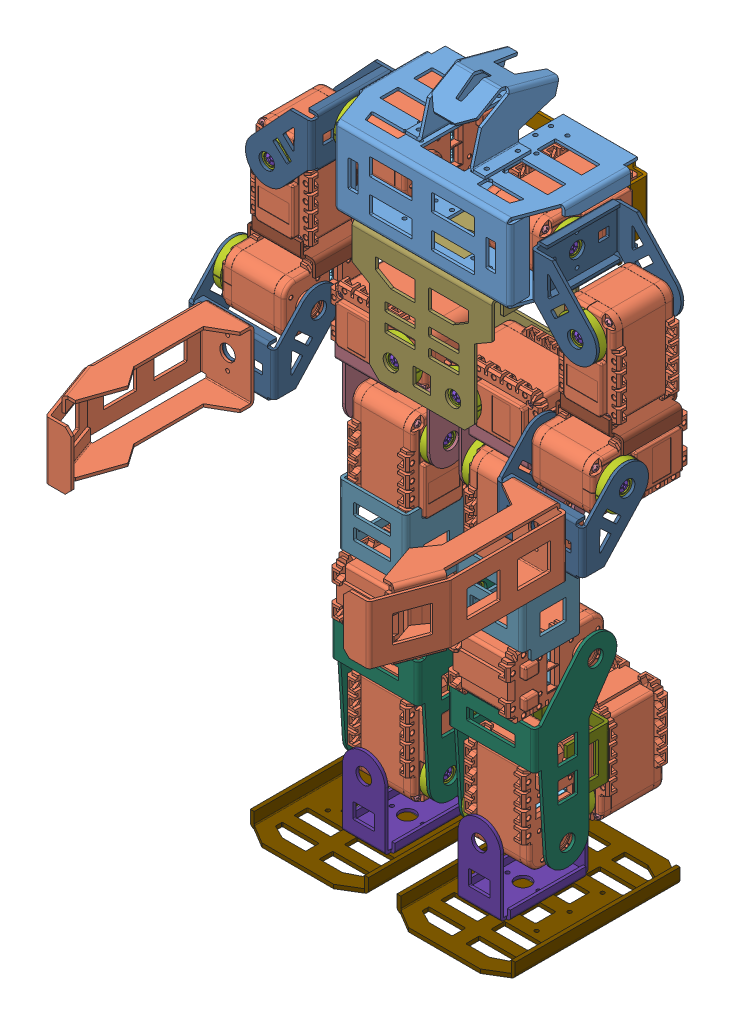
SolidWorks assembly BioloidGP1, configuration Default. Lengths in mm.
Overall size (259 349.06 195.51).
232 component instances, 20 part files, 102 mates.
Components (placement in the parent):
- FR04-E120-1: FR04-E120 [Default] at (-6.1822 -2.1819 114.2456) size (106 40.5 61.5)
- AX-12-18-A-2: AX-12-18-A [Default] at (31.961 8.8095 126.4932) x (0 1 0) z (1 0 0) size (32 50.04 40.18)
  - ASM0002_ASM-1: ASM0002_ASM [Default] at (-10.9914 -11.7476 -2.6432) size (32 50.04 40.18)
    - PRT0001-1: PRT0001 [Default] at origin size (32 50.04 38.06)
    - PRT0002-1: PRT0002 [Default] at (0 0 -2) x (-1 0 0) z (0 0 1) size (6.5 6.5 5.5)
    - PRT0003-1: PRT0003 [Default] at (9.5 8.5 14.5) x (-1 0 0) z (0 1 0) size (3.6 31.47 4.83)
    - PRT0003-2: PRT0003 [Default] at (-9.5 8.5 14.5) x (-1 0 0) z (0 1 0) size (3.6 31.47 4.83)
    - PRT0003-3: PRT0003 [Default] at (10.5 -33 14.5) x (-1 0 0) z (0 1 0) size (3.6 31.47 4.83)
    - PRT0003-4: PRT0003 [Default] at (-10.5 -33 14.5) x (-1 0 0) z (0 1 0) size (3.6 31.47 4.83)
    - PRT0004-1: PRT0004 [Default] at (5.05 -15.19 -9.75) x (1 0 0) z (0 1 0) size (9.9 9.43 4.9)
    - PRT0004-2: PRT0004 [Default] at (-4.95 -15.19 -9.75) x (1 0 0) z (0 1 0) size (9.9 9.43 4.9)
    - PRT0005-1: PRT0005 [Default] at (0 0 -18.4) x (-1 0 0) z (0 1 0) size (4.98 7 4.98)
    - PRT0006-1: PRT0006 [Default] at (0 0 19.16) x (0 1 0) z (0 0 1) size (22 22 6.7)
    - PRT0007-1: PRT0007 [Default] at (0 0 19.48) x (-1 0 0) z (0 1 0) size (5.5 9.69 5.91)
- AX-12-18-A-4: AX-12-18-A [Default] at (-44.3255 -13.1733 126.4932) x (0 -1 0) z (-1 0 0) size (32 50.04 40.18)
  - ASM0002_ASM-1: ASM0002_ASM [Default] at (-10.9914 -11.7476 -2.6432) size (32 50.04 40.18)
    - PRT0001-1: PRT0001 [Default] at origin size (32 50.04 38.06)
    - PRT0002-1: PRT0002 [Default] at (0 0 -2) x (-1 0 0) z (0 0 1) size (6.5 6.5 5.5)
    - PRT0003-1: PRT0003 [Default] at (9.5 8.5 14.5) x (-1 0 0) z (0 1 0) size (3.6 31.47 4.83)
    - PRT0003-2: PRT0003 [Default] at (-9.5 8.5 14.5) x (-1 0 0) z (0 1 0) size (3.6 31.47 4.83)
    - PRT0003-3: PRT0003 [Default] at (10.5 -33 14.5) x (-1 0 0) z (0 1 0) size (3.6 31.47 4.83)
    - PRT0003-4: PRT0003 [Default] at (-10.5 -33 14.5) x (-1 0 0) z (0 1 0) size (3.6 31.47 4.83)
    - PRT0004-1: PRT0004 [Default] at (5.05 -15.19 -9.75) x (1 0 0) z (0 1 0) size (9.9 9.43 4.9)
    - PRT0004-2: PRT0004 [Default] at (-4.95 -15.19 -9.75) x (1 0 0) z (0 1 0) size (9.9 9.43 4.9)
    - PRT0005-1: PRT0005 [Default] at (0 0 -18.4) x (-1 0 0) z (0 1 0) size (4.98 7 4.98)
    - PRT0006-1: PRT0006 [Default] at (0 0 19.16) x (0 1 0) z (0 0 1) size (22 22 6.7)
    - PRT0007-1: PRT0007 [Default] at (0 0 19.48) x (-1 0 0) z (0 1 0) size (5.5 9.69 5.91)
- FR04-E150-1: FR04-E150 [Default] at (-6.1822 -2.1819 115.0456) size (106 53 9.7)
- FR04-H102-1: FR04-H102 [Default] at (73.3178 -20.1819 114.7456) x (0 0 1) z (0 -1 0) size (45.02 34.01 42)
- FR04-H102-2: FR04-H102 [Default] at (-85.6822 -20.1819 114.7456) x (0 0 -1) z (0 -1 0) size (45.02 34.01 42)
- AX-12-18-A-7: AX-12-18-A [Default] at (84.3092 -8.4342 117.3888) size (32 50.04 40.18)
  - ASM0002_ASM-1: ASM0002_ASM [Default] at (-10.9914 -11.7476 -2.6432) size (32 50.04 40.18)
    - PRT0001-1: PRT0001 [Default] at origin size (32 50.04 38.06)
    - PRT0002-1: PRT0002 [Default] at (0 0 -2) x (-1 0 0) z (0 0 1) size (6.5 6.5 5.5)
    - PRT0003-1: PRT0003 [Default] at (9.5 8.5 14.5) x (-1 0 0) z (0 1 0) size (3.6 31.47 4.83)
    - PRT0003-2: PRT0003 [Default] at (-9.5 8.5 14.5) x (-1 0 0) z (0 1 0) size (3.6 31.47 4.83)
    - PRT0003-3: PRT0003 [Default] at (10.5 -33 14.5) x (-1 0 0) z (0 1 0) size (3.6 31.47 4.83)
    - PRT0003-4: PRT0003 [Default] at (-10.5 -33 14.5) x (-1 0 0) z (0 1 0) size (3.6 31.47 4.83)
    - PRT0004-1: PRT0004 [Default] at (5.05 -15.19 -9.75) x (1 0 0) z (0 1 0) size (9.9 9.43 4.9)
    - PRT0004-2: PRT0004 [Default] at (-4.95 -15.19 -9.75) x (1 0 0) z (0 1 0) size (9.9 9.43 4.9)
    - PRT0005-1: PRT0005 [Default] at (0 0 -18.4) x (-1 0 0) z (0 1 0) size (4.98 7 4.98)
    - PRT0006-1: PRT0006 [Default] at (0 0 19.16) x (0 1 0) z (0 0 1) size (22 22 6.7)
    - PRT0007-1: PRT0007 [Default] at (0 0 19.48) x (-1 0 0) z (0 1 0) size (5.5 9.69 5.91)
- AX-12-18-A-8: AX-12-18-A [Default] at (-74.6908 -8.4342 117.3888) size (32 50.04 40.18)
  - ASM0002_ASM-1: ASM0002_ASM [Default] at (-10.9914 -11.7476 -2.6432) size (32 50.04 40.18)
    - PRT0001-1: PRT0001 [Default] at origin size (32 50.04 38.06)
    - PRT0002-1: PRT0002 [Default] at (0 0 -2) x (-1 0 0) z (0 0 1) size (6.5 6.5 5.5)
    - PRT0003-1: PRT0003 [Default] at (9.5 8.5 14.5) x (-1 0 0) z (0 1 0) size (3.6 31.47 4.83)
    - PRT0003-2: PRT0003 [Default] at (-9.5 8.5 14.5) x (-1 0 0) z (0 1 0) size (3.6 31.47 4.83)
    - PRT0003-3: PRT0003 [Default] at (10.5 -33 14.5) x (-1 0 0) z (0 1 0) size (3.6 31.47 4.83)
    - PRT0003-4: PRT0003 [Default] at (-10.5 -33 14.5) x (-1 0 0) z (0 1 0) size (3.6 31.47 4.83)
    - PRT0004-1: PRT0004 [Default] at (5.05 -15.19 -9.75) x (1 0 0) z (0 1 0) size (9.9 9.43 4.9)
    - PRT0004-2: PRT0004 [Default] at (-4.95 -15.19 -9.75) x (1 0 0) z (0 1 0) size (9.9 9.43 4.9)
    - PRT0005-1: PRT0005 [Default] at (0 0 -18.4) x (-1 0 0) z (0 1 0) size (4.98 7 4.98)
    - PRT0006-1: PRT0006 [Default] at (0 0 19.16) x (0 1 0) z (0 0 1) size (22 22 6.7)
    - PRT0007-1: PRT0007 [Default] at (0 0 19.48) x (-1 0 0) z (0 1 0) size (5.5 9.69 5.91)
- AX-12-18-A-9: AX-12-18-A [Default] at (75.961 -66.5905 144.6932) x (0 1 0) z (1 0 0) size (32 50.04 40.18)
  - ASM0002_ASM-1: ASM0002_ASM [Default] at (-10.9914 -11.7476 -2.6432) size (32 50.04 40.18)
    - PRT0001-1: PRT0001 [Default] at origin size (32 50.04 38.06)
    - PRT0002-1: PRT0002 [Default] at (0 0 -2) x (-1 0 0) z (0 0 1) size (6.5 6.5 5.5)
    - PRT0003-1: PRT0003 [Default] at (9.5 8.5 14.5) x (-1 0 0) z (0 1 0) size (3.6 31.47 4.83)
    - PRT0003-2: PRT0003 [Default] at (-9.5 8.5 14.5) x (-1 0 0) z (0 1 0) size (3.6 31.47 4.83)
    - PRT0003-3: PRT0003 [Default] at (10.5 -33 14.5) x (-1 0 0) z (0 1 0) size (3.6 31.47 4.83)
    - PRT0003-4: PRT0003 [Default] at (-10.5 -33 14.5) x (-1 0 0) z (0 1 0) size (3.6 31.47 4.83)
    - PRT0004-1: PRT0004 [Default] at (5.05 -15.19 -9.75) x (1 0 0) z (0 1 0) size (9.9 9.43 4.9)
    - PRT0004-2: PRT0004 [Default] at (-4.95 -15.19 -9.75) x (1 0 0) z (0 1 0) size (9.9 9.43 4.9)
    - PRT0005-1: PRT0005 [Default] at (0 0 -18.4) x (-1 0 0) z (0 1 0) size (4.98 7 4.98)
    - PRT0006-1: PRT0006 [Default] at (0 0 19.16) x (0 1 0) z (0 0 1) size (22 22 6.7)
    - PRT0007-1: PRT0007 [Default] at (0 0 19.48) x (-1 0 0) z (0 1 0) size (5.5 9.69 5.91)
- AX-12-18-A-10: AX-12-18-A [Default] at (-88.3255 -88.5733 144.6932) x (0 -1 0) z (-1 0 0) size (32 50.04 40.18)
  - ASM0002_ASM-1: ASM0002_ASM [Default] at (-10.9914 -11.7476 -2.6432) size (32 50.04 40.18)
    - PRT0001-1: PRT0001 [Default] at origin size (32 50.04 38.06)
    - PRT0002-1: PRT0002 [Default] at (0 0 -2) x (-1 0 0) z (0 0 1) size (6.5 6.5 5.5)
    - PRT0003-1: PRT0003 [Default] at (9.5 8.5 14.5) x (-1 0 0) z (0 1 0) size (3.6 31.47 4.83)
    - PRT0003-2: PRT0003 [Default] at (-9.5 8.5 14.5) x (-1 0 0) z (0 1 0) size (3.6 31.47 4.83)
    - PRT0003-3: PRT0003 [Default] at (10.5 -33 14.5) x (-1 0 0) z (0 1 0) size (3.6 31.47 4.83)
    - PRT0003-4: PRT0003 [Default] at (-10.5 -33 14.5) x (-1 0 0) z (0 1 0) size (3.6 31.47 4.83)
    - PRT0004-1: PRT0004 [Default] at (5.05 -15.19 -9.75) x (1 0 0) z (0 1 0) size (9.9 9.43 4.9)
    - PRT0004-2: PRT0004 [Default] at (-4.95 -15.19 -9.75) x (1 0 0) z (0 1 0) size (9.9 9.43 4.9)
    - PRT0005-1: PRT0005 [Default] at (0 0 -18.4) x (-1 0 0) z (0 1 0) size (4.98 7 4.98)
    - PRT0006-1: PRT0006 [Default] at (0 0 19.16) x (0 1 0) z (0 0 1) size (22 22 6.7)
    - PRT0007-1: PRT0007 [Default] at (0 0 19.48) x (-1 0 0) z (0 1 0) size (5.5 9.69 5.91)
- FR04-SC101-3: FR04-SC101 [Default] at (-85.6822 -59.3819 114.7456) size (35 14.9 35)
- FR04-SC101-4: FR04-SC101 [Default] at (73.3178 -59.3819 114.7456) size (35 14.9 35)
- FR04-H102-3: FR04-H102 [Default] at (-85.6822 -77.5819 132.9456) x (-1 0 0) z (0 1 0) size (45.02 34.01 42)
- FR04-H102-4: FR04-H102 [Default] at (73.3178 -77.5819 132.9456) x (-1 0 0) z (0 1 0) size (45.02 34.01 42)
- FR04-E131-1: FR04-E131 [Default] at (-6.1822 -78.6819 114.2456) size (76 64.5 45)
- AX-12-18-A-11: AX-12-18-A [Default] at (-1.9298 -67.6905 116.8888) x (0 1 0) z (0 0 1) size (32 50.04 40.18)
  - ASM0002_ASM-1: ASM0002_ASM [Default] at (-10.9914 -11.7476 -2.6432) size (32 50.04 40.18)
    - PRT0001-1: PRT0001 [Default] at origin size (32 50.04 38.06)
    - PRT0002-1: PRT0002 [Default] at (0 0 -2) x (-1 0 0) z (0 0 1) size (6.5 6.5 5.5)
    - PRT0003-1: PRT0003 [Default] at (9.5 8.5 14.5) x (-1 0 0) z (0 1 0) size (3.6 31.47 4.83)
    - PRT0003-2: PRT0003 [Default] at (-9.5 8.5 14.5) x (-1 0 0) z (0 1 0) size (3.6 31.47 4.83)
    - PRT0003-3: PRT0003 [Default] at (10.5 -33 14.5) x (-1 0 0) z (0 1 0) size (3.6 31.47 4.83)
    - PRT0003-4: PRT0003 [Default] at (-10.5 -33 14.5) x (-1 0 0) z (0 1 0) size (3.6 31.47 4.83)
    - PRT0004-1: PRT0004 [Default] at (5.05 -15.19 -9.75) x (1 0 0) z (0 1 0) size (9.9 9.43 4.9)
    - PRT0004-2: PRT0004 [Default] at (-4.95 -15.19 -9.75) x (1 0 0) z (0 1 0) size (9.9 9.43 4.9)
    - PRT0005-1: PRT0005 [Default] at (0 0 -18.4) x (-1 0 0) z (0 1 0) size (4.98 7 4.98)
    - PRT0006-1: PRT0006 [Default] at (0 0 19.16) x (0 1 0) z (0 0 1) size (22 22 6.7)
    - PRT0007-1: PRT0007 [Default] at (0 0 19.48) x (-1 0 0) z (0 1 0) size (5.5 9.69 5.91)
- AX-12-18-A-13: AX-12-18-A [Default] at (-10.4346 -89.6733 116.8888) x (0 -1 0) z (0 0 1) size (32 50.04 40.18)
  - ASM0002_ASM-1: ASM0002_ASM [Default] at (-10.9914 -11.7476 -2.6432) size (32 50.04 40.18)
    - PRT0001-1: PRT0001 [Default] at origin size (32 50.04 38.06)
    - PRT0002-1: PRT0002 [Default] at (0 0 -2) x (-1 0 0) z (0 0 1) size (6.5 6.5 5.5)
    - PRT0003-1: PRT0003 [Default] at (9.5 8.5 14.5) x (-1 0 0) z (0 1 0) size (3.6 31.47 4.83)
    - PRT0003-2: PRT0003 [Default] at (-9.5 8.5 14.5) x (-1 0 0) z (0 1 0) size (3.6 31.47 4.83)
    - PRT0003-3: PRT0003 [Default] at (10.5 -33 14.5) x (-1 0 0) z (0 1 0) size (3.6 31.47 4.83)
    - PRT0003-4: PRT0003 [Default] at (-10.5 -33 14.5) x (-1 0 0) z (0 1 0) size (3.6 31.47 4.83)
    - PRT0004-1: PRT0004 [Default] at (5.05 -15.19 -9.75) x (1 0 0) z (0 1 0) size (9.9 9.43 4.9)
    - PRT0004-2: PRT0004 [Default] at (-4.95 -15.19 -9.75) x (1 0 0) z (0 1 0) size (9.9 9.43 4.9)
    - PRT0005-1: PRT0005 [Default] at (0 0 -18.4) x (-1 0 0) z (0 1 0) size (4.98 7 4.98)
    - PRT0006-1: PRT0006 [Default] at (0 0 19.16) x (0 1 0) z (0 0 1) size (22 22 6.7)
    - PRT0007-1: PRT0007 [Default] at (0 0 19.48) x (-1 0 0) z (0 1 0) size (5.5 9.69 5.91)
- FR04-HC110-1: FR04-HC110 [Default] at (-36.1822 -120.4819 114.2456) size (45 42.8 35)
- FR04-HC110-2: FR04-HC110 [Default] at (23.8178 -120.4819 114.2456) x (-1 0 0) z (0 0 -1) size (45 42.8 35)
- AX-12-18-A-16: AX-12-18-A [Default] at (21.1745 -108.7342 125.237) x (0 0 1) z (-1 0 0) size (32 50.04 40.18)
  - ASM0002_ASM-1: ASM0002_ASM [Default] at (-10.9914 -11.7476 -2.6432) size (32 50.04 40.18)
    - PRT0001-1: PRT0001 [Default] at origin size (32 50.04 38.06)
    - PRT0002-1: PRT0002 [Default] at (0 0 -2) x (-1 0 0) z (0 0 1) size (6.5 6.5 5.5)
    - PRT0003-1: PRT0003 [Default] at (9.5 8.5 14.5) x (-1 0 0) z (0 1 0) size (3.6 31.47 4.83)
    - PRT0003-2: PRT0003 [Default] at (-9.5 8.5 14.5) x (-1 0 0) z (0 1 0) size (3.6 31.47 4.83)
    - PRT0003-3: PRT0003 [Default] at (10.5 -33 14.5) x (-1 0 0) z (0 1 0) size (3.6 31.47 4.83)
    - PRT0003-4: PRT0003 [Default] at (-10.5 -33 14.5) x (-1 0 0) z (0 1 0) size (3.6 31.47 4.83)
    - PRT0004-1: PRT0004 [Default] at (5.05 -15.19 -9.75) x (1 0 0) z (0 1 0) size (9.9 9.43 4.9)
    - PRT0004-2: PRT0004 [Default] at (-4.95 -15.19 -9.75) x (1 0 0) z (0 1 0) size (9.9 9.43 4.9)
    - PRT0005-1: PRT0005 [Default] at (0 0 -18.4) x (-1 0 0) z (0 1 0) size (4.98 7 4.98)
    - PRT0006-1: PRT0006 [Default] at (0 0 19.16) x (0 1 0) z (0 0 1) size (22 22 6.7)
    - PRT0007-1: PRT0007 [Default] at (0 0 19.48) x (-1 0 0) z (0 1 0) size (5.5 9.69 5.91)
- AX-12-18-A-17: AX-12-18-A [Default] at (-33.539 -108.7342 103.2542) x (0 0 -1) z (1 0 0) size (32 50.04 40.18)
  - ASM0002_ASM-1: ASM0002_ASM [Default] at (-10.9914 -11.7476 -2.6432) size (32 50.04 40.18)
    - PRT0001-1: PRT0001 [Default] at origin size (32 50.04 38.06)
    - PRT0002-1: PRT0002 [Default] at (0 0 -2) x (-1 0 0) z (0 0 1) size (6.5 6.5 5.5)
    - PRT0003-1: PRT0003 [Default] at (9.5 8.5 14.5) x (-1 0 0) z (0 1 0) size (3.6 31.47 4.83)
    - PRT0003-2: PRT0003 [Default] at (-9.5 8.5 14.5) x (-1 0 0) z (0 1 0) size (3.6 31.47 4.83)
    - PRT0003-3: PRT0003 [Default] at (10.5 -33 14.5) x (-1 0 0) z (0 1 0) size (3.6 31.47 4.83)
    - PRT0003-4: PRT0003 [Default] at (-10.5 -33 14.5) x (-1 0 0) z (0 1 0) size (3.6 31.47 4.83)
    - PRT0004-1: PRT0004 [Default] at (5.05 -15.19 -9.75) x (1 0 0) z (0 1 0) size (9.9 9.43 4.9)
    - PRT0004-2: PRT0004 [Default] at (-4.95 -15.19 -9.75) x (1 0 0) z (0 1 0) size (9.9 9.43 4.9)
    - PRT0005-1: PRT0005 [Default] at (0 0 -18.4) x (-1 0 0) z (0 1 0) size (4.98 7 4.98)
    - PRT0006-1: PRT0006 [Default] at (0 0 19.16) x (0 1 0) z (0 0 1) size (22 22 6.7)
    - PRT0007-1: PRT0007 [Default] at (0 0 19.48) x (-1 0 0) z (0 1 0) size (5.5 9.69 5.91)
- FR04-SC110-1: FR04-SC110 [Default] at (-36.1822 -120.1819 113.9456) size (35 37.2 29.5)
- FR04-SC110-2: FR04-SC110 [Default] at (23.8178 -120.1819 113.9456) size (35 37.2 29.5)
- AX-12-18-A-18: AX-12-18-A [Default] at (21.1745 -183.8905 87.9979) x (0 1 0) z (-1 0 0) size (32 50.04 40.18)
  - ASM0002_ASM-1: ASM0002_ASM [Default] at (-10.9914 -11.7476 -2.6432) size (32 50.04 40.18)
    - PRT0001-1: PRT0001 [Default] at origin size (32 50.04 38.06)
    - PRT0002-1: PRT0002 [Default] at (0 0 -2) x (-1 0 0) z (0 0 1) size (6.5 6.5 5.5)
    - PRT0003-1: PRT0003 [Default] at (9.5 8.5 14.5) x (-1 0 0) z (0 1 0) size (3.6 31.47 4.83)
    - PRT0003-2: PRT0003 [Default] at (-9.5 8.5 14.5) x (-1 0 0) z (0 1 0) size (3.6 31.47 4.83)
    - PRT0003-3: PRT0003 [Default] at (10.5 -33 14.5) x (-1 0 0) z (0 1 0) size (3.6 31.47 4.83)
    - PRT0003-4: PRT0003 [Default] at (-10.5 -33 14.5) x (-1 0 0) z (0 1 0) size (3.6 31.47 4.83)
    - PRT0004-1: PRT0004 [Default] at (5.05 -15.19 -9.75) x (1 0 0) z (0 1 0) size (9.9 9.43 4.9)
    - PRT0004-2: PRT0004 [Default] at (-4.95 -15.19 -9.75) x (1 0 0) z (0 1 0) size (9.9 9.43 4.9)
    - PRT0005-1: PRT0005 [Default] at (0 0 -18.4) x (-1 0 0) z (0 1 0) size (4.98 7 4.98)
    - PRT0006-1: PRT0006 [Default] at (0 0 19.16) x (0 1 0) z (0 0 1) size (22 22 6.7)
    - PRT0007-1: PRT0007 [Default] at (0 0 19.48) x (-1 0 0) z (0 1 0) size (5.5 9.69 5.91)
- AX-12-18-A-19: AX-12-18-A [Default] at (-33.539 -205.8733 87.9979) x (0 -1 0) z (1 0 0) size (32 50.04 40.18)
  - ASM0002_ASM-1: ASM0002_ASM [Default] at (-10.9914 -11.7476 -2.6432) size (32 50.04 40.18)
    - PRT0001-1: PRT0001 [Default] at origin size (32 50.04 38.06)
    - PRT0002-1: PRT0002 [Default] at (0 0 -2) x (-1 0 0) z (0 0 1) size (6.5 6.5 5.5)
    - PRT0003-1: PRT0003 [Default] at (9.5 8.5 14.5) x (-1 0 0) z (0 1 0) size (3.6 31.47 4.83)
    - PRT0003-2: PRT0003 [Default] at (-9.5 8.5 14.5) x (-1 0 0) z (0 1 0) size (3.6 31.47 4.83)
    - PRT0003-3: PRT0003 [Default] at (10.5 -33 14.5) x (-1 0 0) z (0 1 0) size (3.6 31.47 4.83)
    - PRT0003-4: PRT0003 [Default] at (-10.5 -33 14.5) x (-1 0 0) z (0 1 0) size (3.6 31.47 4.83)
    - PRT0004-1: PRT0004 [Default] at (5.05 -15.19 -9.75) x (1 0 0) z (0 1 0) size (9.9 9.43 4.9)
    - PRT0004-2: PRT0004 [Default] at (-4.95 -15.19 -9.75) x (1 0 0) z (0 1 0) size (9.9 9.43 4.9)
    - PRT0005-1: PRT0005 [Default] at (0 0 -18.4) x (-1 0 0) z (0 1 0) size (4.98 7 4.98)
    - PRT0006-1: PRT0006 [Default] at (0 0 19.16) x (0 1 0) z (0 0 1) size (22 22 6.7)
    - PRT0007-1: PRT0007 [Default] at (0 0 19.48) x (-1 0 0) z (0 1 0) size (5.5 9.69 5.91)
- FR04-H120-1: FR04-H120 [Default] at (-36.1822 -269.8819 114.2456) x (-1 0 0) z (0 0 1) size (45 97 42.5)
- FR04-H120-2: FR04-H120 [Default] at (23.8178 -269.8819 114.2456) x (-1 0 0) z (0 0 1) size (45 97 42.5)
- AX-12-18-A-20: AX-12-18-A [Default] at (-33.539 -281.6295 125.237) x (0 0 1) z (1 0 0) size (32 50.04 40.18)
  - ASM0002_ASM-1: ASM0002_ASM [Default] at (-10.9914 -11.7476 -2.6432) size (32 50.04 40.18)
    - PRT0001-1: PRT0001 [Default] at origin size (32 50.04 38.06)
    - PRT0002-1: PRT0002 [Default] at (0 0 -2) x (-1 0 0) z (0 0 1) size (6.5 6.5 5.5)
    - PRT0003-1: PRT0003 [Default] at (9.5 8.5 14.5) x (-1 0 0) z (0 1 0) size (3.6 31.47 4.83)
    - PRT0003-2: PRT0003 [Default] at (-9.5 8.5 14.5) x (-1 0 0) z (0 1 0) size (3.6 31.47 4.83)
    - PRT0003-3: PRT0003 [Default] at (10.5 -33 14.5) x (-1 0 0) z (0 1 0) size (3.6 31.47 4.83)
    - PRT0003-4: PRT0003 [Default] at (-10.5 -33 14.5) x (-1 0 0) z (0 1 0) size (3.6 31.47 4.83)
    - PRT0004-1: PRT0004 [Default] at (5.05 -15.19 -9.75) x (1 0 0) z (0 1 0) size (9.9 9.43 4.9)
    - PRT0004-2: PRT0004 [Default] at (-4.95 -15.19 -9.75) x (1 0 0) z (0 1 0) size (9.9 9.43 4.9)
    - PRT0005-1: PRT0005 [Default] at (0 0 -18.4) x (-1 0 0) z (0 1 0) size (4.98 7 4.98)
    - PRT0006-1: PRT0006 [Default] at (0 0 19.16) x (0 1 0) z (0 0 1) size (22 22 6.7)
    - PRT0007-1: PRT0007 [Default] at (0 0 19.48) x (-1 0 0) z (0 1 0) size (5.5 9.69 5.91)
- AX-12-18-A-21: AX-12-18-A [Default] at (21.1745 -281.6295 103.2542) x (0 0 -1) z (-1 0 0) size (32 50.04 40.18)
  - ASM0002_ASM-1: ASM0002_ASM [Default] at (-10.9914 -11.7476 -2.6432) size (32 50.04 40.18)
    - PRT0001-1: PRT0001 [Default] at origin size (32 50.04 38.06)
    - PRT0002-1: PRT0002 [Default] at (0 0 -2) x (-1 0 0) z (0 0 1) size (6.5 6.5 5.5)
    - PRT0003-1: PRT0003 [Default] at (9.5 8.5 14.5) x (-1 0 0) z (0 1 0) size (3.6 31.47 4.83)
    - PRT0003-2: PRT0003 [Default] at (-9.5 8.5 14.5) x (-1 0 0) z (0 1 0) size (3.6 31.47 4.83)
    - PRT0003-3: PRT0003 [Default] at (10.5 -33 14.5) x (-1 0 0) z (0 1 0) size (3.6 31.47 4.83)
    - PRT0003-4: PRT0003 [Default] at (-10.5 -33 14.5) x (-1 0 0) z (0 1 0) size (3.6 31.47 4.83)
    - PRT0004-1: PRT0004 [Default] at (5.05 -15.19 -9.75) x (1 0 0) z (0 1 0) size (9.9 9.43 4.9)
    - PRT0004-2: PRT0004 [Default] at (-4.95 -15.19 -9.75) x (1 0 0) z (0 1 0) size (9.9 9.43 4.9)
    - PRT0005-1: PRT0005 [Default] at (0 0 -18.4) x (-1 0 0) z (0 1 0) size (4.98 7 4.98)
    - PRT0006-1: PRT0006 [Default] at (0 0 19.16) x (0 1 0) z (0 0 1) size (22 22 6.7)
    - PRT0007-1: PRT0007 [Default] at (0 0 19.48) x (-1 0 0) z (0 1 0) size (5.5 9.69 5.91)
- FR04-X101-1: FR04-X101 [Default] at (-36.1822 -247.6819 100.9456) x (1 0 0) z (0 1 0) size (35 22.5 26.5)
- FR04-X101-2: FR04-X101 [Default] at (23.8178 -247.6819 100.9456) x (1 0 0) z (0 1 0) size (35 22.5 26.5)
- AX-12-18-A-22: AX-12-18-A [Default] at (-46.9736 -281.7295 73.5888) x (-1 0 0) z (0 0 1) size (32 50.04 40.18)
  - ASM0002_ASM-1: ASM0002_ASM [Default] at (-10.9914 -11.7476 -2.6432) size (32 50.04 40.18)
    - PRT0001-1: PRT0001 [Default] at origin size (32 50.04 38.06)
    - PRT0002-1: PRT0002 [Default] at (0 0 -2) x (-1 0 0) z (0 0 1) size (6.5 6.5 5.5)
    - PRT0003-1: PRT0003 [Default] at (9.5 8.5 14.5) x (-1 0 0) z (0 1 0) size (3.6 31.47 4.83)
    - PRT0003-2: PRT0003 [Default] at (-9.5 8.5 14.5) x (-1 0 0) z (0 1 0) size (3.6 31.47 4.83)
    - PRT0003-3: PRT0003 [Default] at (10.5 -33 14.5) x (-1 0 0) z (0 1 0) size (3.6 31.47 4.83)
    - PRT0003-4: PRT0003 [Default] at (-10.5 -33 14.5) x (-1 0 0) z (0 1 0) size (3.6 31.47 4.83)
    - PRT0004-1: PRT0004 [Default] at (5.05 -15.19 -9.75) x (1 0 0) z (0 1 0) size (9.9 9.43 4.9)
    - PRT0004-2: PRT0004 [Default] at (-4.95 -15.19 -9.75) x (1 0 0) z (0 1 0) size (9.9 9.43 4.9)
    - PRT0005-1: PRT0005 [Default] at (0 0 -18.4) x (-1 0 0) z (0 1 0) size (4.98 7 4.98)
    - PRT0006-1: PRT0006 [Default] at (0 0 19.16) x (0 1 0) z (0 0 1) size (22 22 6.7)
    - PRT0007-1: PRT0007 [Default] at (0 0 19.48) x (-1 0 0) z (0 1 0) size (5.5 9.69 5.91)
- AX-12-18-A-23: AX-12-18-A [Default] at (12.6264 -281.7295 73.5888) x (-1 0 0) z (0 0 1) size (32 50.04 40.18)
  - ASM0002_ASM-1: ASM0002_ASM [Default] at (-10.9914 -11.7476 -2.6432) size (32 50.04 40.18)
    - PRT0001-1: PRT0001 [Default] at origin size (32 50.04 38.06)
    - PRT0002-1: PRT0002 [Default] at (0 0 -2) x (-1 0 0) z (0 0 1) size (6.5 6.5 5.5)
    - PRT0003-1: PRT0003 [Default] at (9.5 8.5 14.5) x (-1 0 0) z (0 1 0) size (3.6 31.47 4.83)
    - PRT0003-2: PRT0003 [Default] at (-9.5 8.5 14.5) x (-1 0 0) z (0 1 0) size (3.6 31.47 4.83)
    - PRT0003-3: PRT0003 [Default] at (10.5 -33 14.5) x (-1 0 0) z (0 1 0) size (3.6 31.47 4.83)
    - PRT0003-4: PRT0003 [Default] at (-10.5 -33 14.5) x (-1 0 0) z (0 1 0) size (3.6 31.47 4.83)
    - PRT0004-1: PRT0004 [Default] at (5.05 -15.19 -9.75) x (1 0 0) z (0 1 0) size (9.9 9.43 4.9)
    - PRT0004-2: PRT0004 [Default] at (-4.95 -15.19 -9.75) x (1 0 0) z (0 1 0) size (9.9 9.43 4.9)
    - PRT0005-1: PRT0005 [Default] at (0 0 -18.4) x (-1 0 0) z (0 1 0) size (4.98 7 4.98)
    - PRT0006-1: PRT0006 [Default] at (0 0 19.16) x (0 1 0) z (0 0 1) size (22 22 6.7)
    - PRT0007-1: PRT0007 [Default] at (0 0 19.48) x (-1 0 0) z (0 1 0) size (5.5 9.69 5.91)
- FR04-H101-1: FR04-H101 [Default] at (-35.9822 -269.9819 114.4456) x (0 0 1) z (1 0 0) size (45 41 26)
- FR04-H101-2: FR04-H101 [Default] at (23.6178 -269.9819 114.4456) x (0 0 -1) z (-1 0 0) size (45 41 26)
- FR04-E160-1: FR04-E160 [Default] at (-43.9822 -299.9819 114.4456) size (61 8 97)
- FR04-E160-2: FR04-E160 [Default] at (31.6178 -299.9819 114.4456) size (61 8 97)
- FR04-E175-1: FR04-E175 [Default] at (-6.1822 15.3181 124.7294) x (1 0 0) z (0 0.258819 0.965926) size (41 31.63 43.12)
- FR04-E180-1: FR04-E180 [Default] at (-85.6822 -95.5819 155.9456) x (1 0 0) z (0 1 0) size (27 91.51 36)
- FR04-E180-2: FR04-E180 [Default] at (73.3178 -95.5819 155.9456) x (-1 0 0) z (0 -1 0) size (27 91.51 36)
Mates (geometry in assembly coordinates):
- Coincident2: coincident anti-aligned: plane of FR04-E120-1 through (45.3178 -2.1819 114.2456) normal (-1 0 0); plane of AX-12-18-A-2/ASM0002_ASM-1/PRT0001-1 through (45.3178 -2.1819 114.7456) normal (1 0 0)
- Coincident4: coincident anti-aligned: plane of FR04-E120-1 through (-59.2222 13.8181 135.9356) normal (0 -1 0); plane of AX-12-18-A-2/ASM0002_ASM-1/PRT0001-1 through (45.3178 13.8181 112.7456) normal (0 1 0)
- Coincident6: coincident anti-aligned: plane of FR04-E120-1 through (-57.6822 -2.1819 114.2456) normal (1 0 0); plane of AX-12-18-A-4/ASM0002_ASM-1/PRT0001-1 through (-57.6822 -2.1819 114.7456) normal (-1 0 0)
- Coincident7: coincident anti-aligned: plane of FR04-E120-1 through (-59.2222 13.8181 135.9356) normal (0 -1 0); plane of AX-12-18-A-4/ASM0002_ASM-1/PRT0001-1 through (-57.6822 13.8181 79.7456) normal (0 1 0)
- Coincident8: coincident anti-aligned: plane of FR04-E120-1 through (-59.2222 13.8181 135.9356) normal (0 -1 0); plane of FR04-E150-1 through (-6.1822 13.8181 115.0456) normal (0 1 0)
- Coincident9: coincident anti-aligned: plane of FR04-E120-1 through (-59.2222 -23.6819 74.0556) normal (0 1 0); plane of ? through (-6.1822 -23.6819 114.2456) normal (0 -1 0)
- Coincident10: coincident anti-aligned: plane of FR04-E120-1 through (-6.1822 -2.1819 82.2456) normal (0 0 -1); plane of FR04-E150-1 through (-6.1822 -2.1819 82.2456) normal (0 0 1)
- Coincident11: coincident aligned: plane of FR04-E120-1 through (46.8178 -2.1819 114.2456) normal (1 0 0); plane of FR04-E150-1 through (46.8178 8.0181 82.2456) normal (1 0 0)
- Coincident12: coincident anti-aligned: plane of AX-12-18-A-2/ASM0002_ASM-1/PRT0001-1 through (48.3178 7.8181 82.2456) normal (0 0 -1); plane of FR04-E150-1 through (-6.1822 -2.1819 82.2456) normal (0 0 1)
- Coincident13: coincident anti-aligned: plane of AX-12-18-A-4/ASM0002_ASM-1/PRT0001-1 through (-60.6822 -12.1819 82.2456) normal (0 0 -1); plane of FR04-E150-1 through (-6.1822 -2.1819 82.2456) normal (0 0 1)
- Coincident14: coincident anti-aligned: plane of AX-12-18-A-2/ASM0002_ASM-1/PRT0006-1 through (50.3178 -2.1819 114.7456) normal (1 0 0); plane of FR04-H102-1 through (50.3178 9.7781 93.4256) normal (-1 0 0)
- Concentric1: concentric aligned: cylinder of AX-12-18-A-2/ASM0002_ASM-1/PRT0006-1 through (51.1778 -2.1819 114.7456) axis (1 0 0) radius 2.9; cylinder of FR04-H102-1 through (51.8178 -2.1819 114.7456) axis (1 0 0) radius 4
- Coincident15: coincident anti-aligned: plane of AX-12-18-A-4/ASM0002_ASM-1/PRT0006-1 through (-62.6822 -2.1819 114.7456) normal (-1 0 0); plane of FR04-H102-2 through (-62.6822 9.7781 136.0656) normal (1 0 0)
- Concentric2: concentric aligned: cylinder of AX-12-18-A-4/ASM0002_ASM-1/PRT0006-1 through (-63.5422 -2.1819 114.7456) axis (-1 0 0) radius 2.9; cylinder of FR04-H102-2 through (-64.1822 -2.1819 114.7456) axis (-1 0 0) radius 4
- Coincident16: coincident anti-aligned: plane of FR04-H102-1 through (51.6778 9.6181 135.7456) normal (0 0 -1); plane of AX-12-18-A-7/ASM0002_ASM-1/PRT0006-1 through (73.3178 -20.1819 135.7456) normal (0 0 1)
- Concentric3: concentric anti-aligned: cylinder of FR04-H102-1 through (73.3178 -20.1819 135.7456) axis (0 0 -1) radius 4; cylinder of AX-12-18-A-7/ASM0002_ASM-1/PRT0006-1 through (73.3178 -20.1819 136.6056) axis (0 0 1) radius 2.9
- Coincident18: coincident anti-aligned: plane of FR04-H102-2 through (-97.3232 9.6181 135.7456) normal (0 0 -1); plane of AX-12-18-A-8/ASM0002_ASM-1/PRT0006-1 through (-85.6822 -20.1819 135.7456) normal (0 0 1)
- Concentric4: concentric anti-aligned: cylinder of FR04-H102-2 through (-85.6822 -20.1819 135.7456) axis (0 0 -1) radius 4; cylinder of AX-12-18-A-8/ASM0002_ASM-1/PRT0006-1 through (-85.6822 -20.1819 136.6056) axis (0 0 1) radius 2.9
- Coincident19: coincident anti-aligned: plane of AX-12-18-A-7/ASM0002_ASM-1/PRT0001-1 through (73.3178 -20.1819 130.7456) normal (0 0 1); plane of FR04-SC101-4 through (60.8178 -52.6819 130.7456) normal (0 0 -1)
- Coincident20: coincident anti-aligned: plane of AX-12-18-A-8/ASM0002_ASM-1/PRT0001-1 through (-85.6822 -20.1819 130.7456) normal (0 0 1); plane of FR04-SC101-3 through (-98.1822 -52.6819 130.7456) normal (0 0 -1)
- Coincident21: coincident anti-aligned: plane of AX-12-18-A-7/ASM0002_ASM-1/PRT0001-1 through (83.3178 -52.6819 133.7456) normal (0 -1 0); plane of FR04-SC101-4 through (73.3178 -52.6819 114.7456) normal (0 1 0)
- Coincident22: coincident anti-aligned: plane of AX-12-18-A-8/ASM0002_ASM-1/PRT0001-1 through (-75.6822 -52.6819 133.7456) normal (0 -1 0); plane of FR04-SC101-3 through (-85.6822 -52.6819 114.7456) normal (0 1 0)
- Coincident23: coincident aligned: plane of AX-12-18-A-7/ASM0002_ASM-1/PRT0001-1 through (60.8178 -58.6819 130.7456) normal (-1 0 0); plane of FR04-SC101-4 through (60.8178 -60.8819 97.2456) normal (-1 0 0)
- Coincident24: coincident aligned: plane of AX-12-18-A-8/ASM0002_ASM-1/PRT0001-1 through (-73.1822 -55.6819 130.7456) normal (1 0 0); plane of FR04-SC101-3 through (-73.1822 -60.8819 132.2456) normal (1 0 0)
- Coincident25: coincident anti-aligned: plane of AX-12-18-A-9/ASM0002_ASM-1/PRT0001-1 through (89.3178 -77.5819 132.9456) normal (1 0 0); plane of FR04-SC101-4 through (89.3178 -67.5819 99.7456) normal (-1 0 0)
- Coincident26: coincident anti-aligned: plane of AX-12-18-A-9/ASM0002_ASM-1/PRT0001-1 through (92.3178 -67.5819 144.4456) normal (0 1 0); plane of FR04-SC101-4 through (73.3178 -67.5819 114.7456) normal (0 -1 0)
- Coincident28: coincident aligned: plane of AX-12-18-A-9/ASM0002_ASM-1/PRT0001-1 through (89.3178 -93.5819 129.7456) normal (0 0 1); plane of FR04-SC101-4 through (90.8178 -60.8819 129.7456) normal (0 0 1)
- Coincident29: coincident anti-aligned: plane of AX-12-18-A-10/ASM0002_ASM-1/PRT0001-1 through (-101.6822 -77.5819 132.9456) normal (-1 0 0); plane of FR04-SC101-3 through (-101.6822 -67.5819 129.7456) normal (1 0 0)
- Coincident30: coincident anti-aligned: plane of AX-12-18-A-10/ASM0002_ASM-1/PRT0001-1 through (-104.6822 -67.5819 100.4456) normal (0 1 0); plane of FR04-SC101-3 through (-85.6822 -67.5819 114.7456) normal (0 -1 0)
- Coincident31: coincident aligned: plane of AX-12-18-A-10/ASM0002_ASM-1/PRT0001-1 through (-101.6822 -61.5819 129.7456) normal (0 0 1); plane of FR04-SC101-3 through (-103.1822 -59.3819 129.7456) normal (0 0 1)
- Coincident32: coincident anti-aligned: plane of AX-12-18-A-9/ASM0002_ASM-1/PRT0006-1 through (94.3178 -77.5819 132.9456) normal (1 0 0); plane of FR04-H102-4 through (94.3178 -107.3819 121.3046) normal (-1 0 0)
- Concentric5: concentric anti-aligned: cylinder of AX-12-18-A-9/ASM0002_ASM-1/PRT0006-1 through (95.1778 -77.5819 132.9456) axis (1 0 0) radius 2.9; cylinder of FR04-H102-4 through (94.3178 -77.5819 132.9456) axis (-1 0 0) radius 4
- Coincident33: coincident anti-aligned: plane of AX-12-18-A-10/ASM0002_ASM-1/PRT0006-1 through (-106.6822 -77.5819 132.9456) normal (-1 0 0); plane of FR04-H102-3 through (-106.6822 -107.3819 154.5856) normal (1 0 0)
- Concentric6: concentric anti-aligned: cylinder of AX-12-18-A-10/ASM0002_ASM-1/PRT0006-1 through (-107.5422 -77.5819 132.9456) axis (-1 0 0) radius 2.9; cylinder of FR04-H102-3 through (-106.6822 -77.5819 132.9456) axis (1 0 0) radius 4
- Coincident37: coincident anti-aligned: plane of FR04-E131-1 through (29.8178 -89.6819 135.2456) normal (0 0 -1); plane of AX-12-18-A-11/ASM0002_ASM-1/PRT0006-1 through (9.8178 -78.6819 135.2456) normal (0 0 1)
- Coincident38: coincident anti-aligned: plane of FR04-E131-1 through (29.8178 -89.6819 135.2456) normal (0 0 -1); plane of AX-12-18-A-13/ASM0002_ASM-1/PRT0006-1 through (-22.1822 -78.6819 135.2456) normal (0 0 1)
- Concentric10: concentric anti-aligned: cylinder of FR04-E131-1 through (9.8178 -78.6819 135.2456) axis (0 0 -1) radius 4; cylinder of AX-12-18-A-11/ASM0002_ASM-1/PRT0006-1 through (9.8178 -78.6819 136.1056) axis (0 0 1) radius 2.9
- Concentric11: concentric anti-aligned: cylinder of FR04-E131-1 through (-22.1822 -78.6819 135.2456) axis (0 0 -1) radius 4; cylinder of AX-12-18-A-13/ASM0002_ASM-1/PRT0006-1 through (-22.1822 -78.6819 136.1056) axis (0 0 1) radius 2.9
- Coincident39: coincident anti-aligned: plane of AX-12-18-A-13/ASM0002_ASM-1/PRT0001-1 through (-22.1822 -78.6819 130.2456) normal (0 0 1); plane of FR04-HC110-1 through (-55.9822 -88.6819 130.2456) normal (0 0 -1)
- Coincident40: coincident anti-aligned: plane of AX-12-18-A-11/ASM0002_ASM-1/PRT0001-1 through (9.8178 -78.6819 130.2456) normal (0 0 1); plane of FR04-HC110-2 through (13.0178 -88.6819 130.2456) normal (0 0 -1)
- Coincident41: coincident aligned: plane of AX-12-18-A-11/ASM0002_ASM-1/PRT0001-1 through (43.6178 -93.1819 130.2456) normal (1 0 0); plane of FR04-HC110-2 through (43.6178 -94.9819 131.7456) normal (1 0 0)
- Coincident42: coincident aligned: plane of AX-12-18-A-13/ASM0002_ASM-1/PRT0001-1 through (-55.9822 -93.1819 130.2456) normal (-1 0 0); plane of FR04-HC110-1 through (-55.9822 -96.4819 131.7456) normal (-1 0 0)
- Coincident43: coincident anti-aligned: plane of AX-12-18-A-13/ASM0002_ASM-1/PRT0001-1 through (-10.6822 -88.6819 133.2456) normal (0 -1 0); plane of FR04-HC110-1 through (-36.1822 -88.6819 114.2456) normal (0 1 0)
- Coincident44: coincident anti-aligned: plane of AX-12-18-A-11/ASM0002_ASM-1/PRT0001-1 through (42.3178 -88.6819 133.2456) normal (0 -1 0); plane of FR04-HC110-2 through (23.8178 -88.6819 114.2456) normal (0 1 0)
- Coincident45: coincident anti-aligned: plane of FR04-HC110-1 through (-15.1822 -138.3645 103.2456) normal (-1 0 0); plane of AX-12-18-A-17/ASM0002_ASM-1/PRT0006-1 through (-15.1822 -120.4819 114.2456) normal (1 0 0)
- Concentric12: concentric anti-aligned: cylinder of FR04-HC110-1 through (-15.1822 -120.4819 114.2456) axis (-1 0 0) radius 4; cylinder of AX-12-18-A-17/ASM0002_ASM-1/PRT0006-1 through (-14.3222 -120.4819 114.2456) axis (1 0 0) radius 2.9
- Coincident46: coincident anti-aligned: plane of FR04-HC110-2 through (2.8178 -138.3645 125.2456) normal (1 0 0); plane of AX-12-18-A-16/ASM0002_ASM-1/PRT0006-1 through (2.8178 -120.4819 114.2456) normal (-1 0 0)
- Concentric13: concentric anti-aligned: cylinder of FR04-HC110-2 through (2.8178 -120.4819 114.2456) axis (1 0 0) radius 4; cylinder of AX-12-18-A-16/ASM0002_ASM-1/PRT0006-1 through (1.9578 -120.4819 114.2456) axis (-1 0 0) radius 2.9
- Coincident47: coincident anti-aligned: plane of AX-12-18-A-17/ASM0002_ASM-1/PRT0001-1 through (-20.1822 -120.4819 114.2456) normal (1 0 0); plane of FR04-SC110-1 through (-20.1822 -120.1819 113.9456) normal (-1 0 0)
- Coincident48: coincident anti-aligned: plane of AX-12-18-A-16/ASM0002_ASM-1/PRT0001-1 through (7.8178 -120.4819 114.2456) normal (-1 0 0); plane of FR04-SC110-2 through (7.8178 -178.8819 102.9456) normal (1 0 0)
- Coincident49: coincident anti-aligned: plane of AX-12-18-A-16/ASM0002_ASM-1/PRT0001-1 through (4.8178 -108.9819 124.2456) normal (0 0 1); plane of FR04-SC110-2 through (41.3178 -152.9819 124.2456) normal (0 0 -1)
- Coincident50: coincident anti-aligned: plane of AX-12-18-A-16/ASM0002_ASM-1/PRT0001-1 through (4.8178 -152.9819 124.2456) normal (0 -1 0); plane of FR04-SC110-2 through (41.3178 -152.9819 102.9456) normal (0 1 0)
- Coincident51: coincident anti-aligned: plane of AX-12-18-A-17/ASM0002_ASM-1/PRT0001-1 through (-17.1822 -152.9819 104.2456) normal (0 -1 0); plane of FR04-SC110-1 through (-53.6832 -152.9819 124.2456) normal (0 1 0)
- Coincident52: coincident anti-aligned: plane of AX-12-18-A-17/ASM0002_ASM-1/PRT0001-1 through (-17.1822 -152.9819 124.2456) normal (0 0 1); plane of FR04-SC110-1 through (-53.6832 -147.6819 124.2456) normal (0 0 -1)
- Coincident53: coincident anti-aligned: plane of FR04-SC110-1 through (-18.6822 -184.8819 102.9456) normal (0 -1 0); plane of AX-12-18-A-19/ASM0002_ASM-1/PRT0001-1 through (-17.1822 -184.8819 132.2456) normal (0 1 0)
- Coincident54: coincident anti-aligned: plane of FR04-SC110-2 through (23.8178 -184.8819 113.9456) normal (0 -1 0); plane of AX-12-18-A-18/ASM0002_ASM-1/PRT0001-1 through (4.8178 -184.8819 88.2456) normal (0 1 0)
- Coincident55: coincident anti-aligned: plane of FR04-SC110-1 through (-20.1822 -120.1819 113.9456) normal (-1 0 0); plane of AX-12-18-A-19/ASM0002_ASM-1/PRT0001-1 through (-20.1822 -194.8819 99.7456) normal (1 0 0)
- Coincident56: coincident anti-aligned: plane of FR04-SC110-2 through (7.8178 -178.8819 102.9456) normal (1 0 0); plane of AX-12-18-A-18/ASM0002_ASM-1/PRT0001-1 through (7.8178 -194.8819 99.7456) normal (-1 0 0)
- Coincident57: coincident aligned: plane of FR04-SC110-1 through (-18.6822 -147.6819 102.9456) normal (0 0 -1); plane of AX-12-18-A-19/ASM0002_ASM-1/PRT0001-1 through (-20.1822 -178.8819 102.9456) normal (0 0 -1)
- Coincident58: coincident aligned: plane of FR04-SC110-2 through (23.8178 -120.1819 102.9456) normal (0 0 -1); plane of AX-12-18-A-18/ASM0002_ASM-1/PRT0001-1 through (7.8178 -210.8819 102.9456) normal (0 0 -1)
- Coincident59: coincident anti-aligned: plane of AX-12-18-A-19/ASM0002_ASM-1/PRT0006-1 through (-15.1822 -194.8819 99.7456) normal (1 0 0); plane of FR04-H120-1 through (-15.1822 -194.8819 99.7456) normal (-1 0 0)
- Concentric14: concentric anti-aligned: cylinder of AX-12-18-A-19/ASM0002_ASM-1/PRT0006-1 through (-14.3222 -194.8819 99.7456) axis (1 0 0) radius 2.9; cylinder of FR04-H120-1 through (-15.1822 -194.8819 99.7456) axis (-1 0 0) radius 4
- Coincident60: coincident anti-aligned: plane of AX-12-18-A-18/ASM0002_ASM-1/PRT0006-1 through (2.8178 -194.8819 99.7456) normal (-1 0 0); plane of FR04-H120-2 through (2.8178 -269.8819 114.2456) normal (1 0 0)
- Concentric15: concentric anti-aligned: cylinder of AX-12-18-A-18/ASM0002_ASM-1/PRT0006-1 through (1.9578 -194.8819 99.7456) axis (-1 0 0) radius 2.9; cylinder of FR04-H120-2 through (2.8178 -194.8819 99.7456) axis (1 0 0) radius 4
- Coincident61: coincident anti-aligned: plane of FR04-H120-1 through (-15.1822 -194.8819 99.7456) normal (-1 0 0); plane of AX-12-18-A-20/ASM0002_ASM-1/PRT0006-1 through (-15.1822 -269.8819 114.2456) normal (1 0 0)
- Concentric16: concentric anti-aligned: cylinder of FR04-H120-1 through (-15.1822 -269.8819 114.2456) axis (-1 0 0) radius 4; cylinder of AX-12-18-A-20/ASM0002_ASM-1/PRT0006-1 through (-14.3222 -269.8819 114.2456) axis (1 0 0) radius 2.9
- Coincident62: coincident anti-aligned: plane of FR04-H120-2 through (2.8178 -269.8819 114.2456) normal (1 0 0); plane of AX-12-18-A-21/ASM0002_ASM-1/PRT0006-1 through (2.8178 -269.8819 114.2456) normal (-1 0 0)
- Concentric17: concentric anti-aligned: cylinder of FR04-H120-2 through (2.8178 -269.8819 114.2456) axis (1 0 0) radius 4; cylinder of AX-12-18-A-21/ASM0002_ASM-1/PRT0006-1 through (1.9578 -269.8819 114.2456) axis (-1 0 0) radius 2.9
- Coincident63: coincident anti-aligned: plane of AX-12-18-A-21/ASM0002_ASM-1/PRT0001-1 through (7.8178 -269.8819 114.2456) normal (-1 0 0); plane of FR04-X101-2 through (7.8178 -258.1819 88.4456) normal (1 0 0)
- Coincident64: coincident anti-aligned: plane of AX-12-18-A-21/ASM0002_ASM-1/PRT0001-1 through (4.8178 -281.3819 104.2456) normal (0 0 -1); plane of FR04-X101-2 through (6.3178 -258.1819 104.2456) normal (0 0 1)
- Coincident65: coincident anti-aligned: plane of AX-12-18-A-21/ASM0002_ASM-1/PRT0001-1 through (4.8178 -237.3819 104.2456) normal (0 1 0); plane of FR04-X101-2 through (6.3178 -237.3819 104.2456) normal (0 -1 0)
- Coincident66: coincident anti-aligned: plane of AX-12-18-A-20/ASM0002_ASM-1/PRT0001-1 through (-20.1822 -269.8819 114.2456) normal (1 0 0); plane of FR04-X101-1 through (-20.1822 -258.1819 109.4456) normal (-1 0 0)
- Coincident67: coincident anti-aligned: plane of AX-12-18-A-20/ASM0002_ASM-1/PRT0001-1 through (-17.1822 -237.3819 104.2456) normal (0 0 -1); plane of FR04-X101-1 through (-18.6822 -237.3819 104.2456) normal (0 0 1)
- Coincident68: coincident anti-aligned: plane of AX-12-18-A-20/ASM0002_ASM-1/PRT0001-1 through (-17.1822 -237.3819 124.2456) normal (0 1 0); plane of FR04-X101-1 through (-18.6822 -237.3819 109.4456) normal (0 -1 0)
- Coincident69: coincident anti-aligned: plane of FR04-X101-2 through (23.8178 -247.6819 86.9456) normal (0 0 -1); plane of AX-12-18-A-23/ASM0002_ASM-1/PRT0001-1 through (23.6178 -269.9819 86.9456) normal (0 0 1)
- Coincident70: coincident anti-aligned: plane of FR04-X101-1 through (-36.1822 -247.6819 86.9456) normal (0 0 -1); plane of AX-12-18-A-22/ASM0002_ASM-1/PRT0001-1 through (-35.9822 -269.9819 86.9456) normal (0 0 1)
- Coincident71: coincident anti-aligned: plane of FR04-X101-1 through (-25.9822 -258.1819 86.9456) normal (-1 0 0); plane of AX-12-18-A-22/ASM0002_ASM-1/PRT0001-1 through (-25.9822 -237.4819 89.9456) normal (1 0 0)
- Coincident72: coincident anti-aligned: plane of FR04-X101-2 through (13.6178 -237.4819 86.9456) normal (1 0 0); plane of AX-12-18-A-23/ASM0002_ASM-1/PRT0001-1 through (13.6178 -281.4819 89.9456) normal (-1 0 0)
- Coincident73: coincident anti-aligned: plane of FR04-X101-2 through (34.0178 -237.4819 86.9456) normal (0 -1 0); plane of AX-12-18-A-23/ASM0002_ASM-1/PRT0001-1 through (13.6178 -237.4819 89.9456) normal (0 1 0)
- Coincident74: coincident anti-aligned: plane of FR04-X101-1 through (-25.9822 -237.4819 86.9456) normal (0 -1 0); plane of AX-12-18-A-22/ASM0002_ASM-1/PRT0001-1 through (-45.9822 -237.4819 89.9456) normal (0 1 0)
- Coincident75: coincident anti-aligned: plane of AX-12-18-A-23/ASM0002_ASM-1/PRT0006-1 through (23.6178 -269.9819 91.9456) normal (0 0 1); plane of FR04-H101-2 through (23.6178 -269.9819 91.9456) normal (0 0 -1)
- Concentric18: concentric aligned: cylinder of AX-12-18-A-23/ASM0002_ASM-1/PRT0006-1 through (23.6178 -269.9819 92.8056) axis (0 0 1) radius 2.9; cylinder of FR04-H101-2 through (23.6178 -269.9819 93.4456) axis (0 0 1) radius 4
- Coincident76: coincident anti-aligned: plane of AX-12-18-A-22/ASM0002_ASM-1/PRT0006-1 through (-35.9822 -269.9819 91.9456) normal (0 0 1); plane of FR04-H101-1 through (-35.9822 -269.9819 91.9456) normal (0 0 -1)
- Concentric19: concentric aligned: cylinder of AX-12-18-A-22/ASM0002_ASM-1/PRT0006-1 through (-35.9822 -269.9819 92.8056) axis (0 0 1) radius 2.9; cylinder of FR04-H101-1 through (-35.9822 -269.9819 93.4456) axis (0 0 1) radius 4
- Coincident77: coincident anti-aligned: plane of FR04-H101-1 through (-46.9822 -299.9819 91.9456) normal (0 -1 0); plane of FR04-E160-1 through (-73.6222 -299.9819 164.8856) normal (0 1 0)
- Coincident78: coincident anti-aligned: plane of FR04-H101-2 through (34.6178 -299.9819 136.9456) normal (0 -1 0); plane of FR04-E160-2 through (1.9778 -299.9819 164.8856) normal (0 1 0)
- Concentric23: concentric aligned: cylinder of FR04-H101-1 through (-27.9822 -297.9819 114.4456) axis (0 -1 0) radius 1; cylinder of FR04-E160-1 through (-27.9822 -299.9819 114.4456) axis (0 -1 0) radius 1
- Concentric24: concentric aligned: cylinder of FR04-H101-1 through (-43.9822 -297.9819 114.4456) axis (0 -1 0) radius 1; cylinder of FR04-E160-1 through (-43.9822 -299.9819 114.4456) axis (0 -1 0) radius 1
- Concentric25: concentric aligned: cylinder of FR04-H101-2 through (31.6178 -297.9819 114.4456) axis (0 -1 0) radius 1; cylinder of FR04-E160-2 through (31.6178 -299.9819 114.4456) axis (0 -1 0) radius 1
- Concentric26: concentric aligned: cylinder of FR04-H101-2 through (15.6178 -297.9819 114.4456) axis (0 -1 0) radius 1; cylinder of FR04-E160-2 through (15.6178 -299.9819 114.4456) axis (0 -1 0) radius 1
- Coincident88: coincident anti-aligned: plane of FR04-E120-1 through (-59.2222 15.3181 135.9356) normal (0 1 0); plane of FR04-E175-1 through (8.1978 15.3181 125.2056) normal (0 -1 0)
- Concentric42: concentric anti-aligned: cylinder of FR04-E120-1 through (11.3178 13.3181 120.8237) axis (0 1 0) radius 1; cylinder of FR04-E175-1 through (11.3178 17.3181 120.8237) axis (0 -1 0) radius 1
- Concentric44: concentric anti-aligned: cylinder of FR04-E120-1 through (-23.6822 13.3181 104.8237) axis (0 1 0) radius 1; cylinder of FR04-E175-1 through (-23.6822 17.3181 104.8237) axis (0 -1 0) radius 1
- Coincident89: coincident anti-aligned: plane of FR04-H102-3 through (-64.3622 -107.5419 155.9456) normal (0 0 1); plane of FR04-E180-1 through (-99.1822 -112.2219 155.9456) normal (0 0 -1)
- Coincident90: coincident anti-aligned: plane of FR04-H102-4 through (94.6378 -107.5419 155.9456) normal (0 0 1); plane of FR04-E180-2 through (86.8178 -78.9419 155.9456) normal (0 0 -1)
- Concentric45: concentric anti-aligned: cylinder of FR04-H102-4 through (73.3178 -87.5819 153.9456) axis (0 0 1) radius 1; cylinder of FR04-E180-2 through (73.3178 -87.5819 157.9456) axis (0 0 -1) radius 1
- Concentric46: concentric anti-aligned: cylinder of FR04-H102-4 through (73.3178 -103.5819 153.9456) axis (0 0 1) radius 1; cylinder of FR04-E180-2 through (73.3178 -103.5819 157.9456) axis (0 0 -1) radius 1
- Concentric47: concentric anti-aligned: cylinder of FR04-H102-3 through (-85.6822 -103.5819 153.9456) axis (0 0 1) radius 1; cylinder of FR04-E180-1 through (-85.6822 -103.5819 157.9456) axis (0 0 -1) radius 1
- Concentric48: concentric anti-aligned: cylinder of FR04-H102-3 through (-85.6822 -87.5819 153.9456) axis (0 0 1) radius 1; cylinder of FR04-E180-1 through (-85.6822 -87.5819 157.9456) axis (0 0 -1) radius 1
- Coincident91: coincident anti-aligned: plane of FR04-E120-1 through (-59.2222 -25.1819 74.0556) normal (0 -1 0); plane of FR04-E131-1 through (-6.1822 -25.1819 114.2456) normal (0 1 0)
- Concentric49: concentric anti-aligned: cylinder of FR04-E120-1 through (-19.6822 15.3181 123.7456) axis (0 -1 0) radius 1; cylinder of FR04-E131-1 through (-19.6822 -26.6819 123.7456) axis (0 1 0) radius 1
- Concentric51: concentric anti-aligned: cylinder of FR04-E120-1 through (7.3178 15.3181 123.7456) axis (0 -1 0) radius 1; cylinder of FR04-E131-1 through (7.3178 -26.6819 123.7456) axis (0 1 0) radius 1
